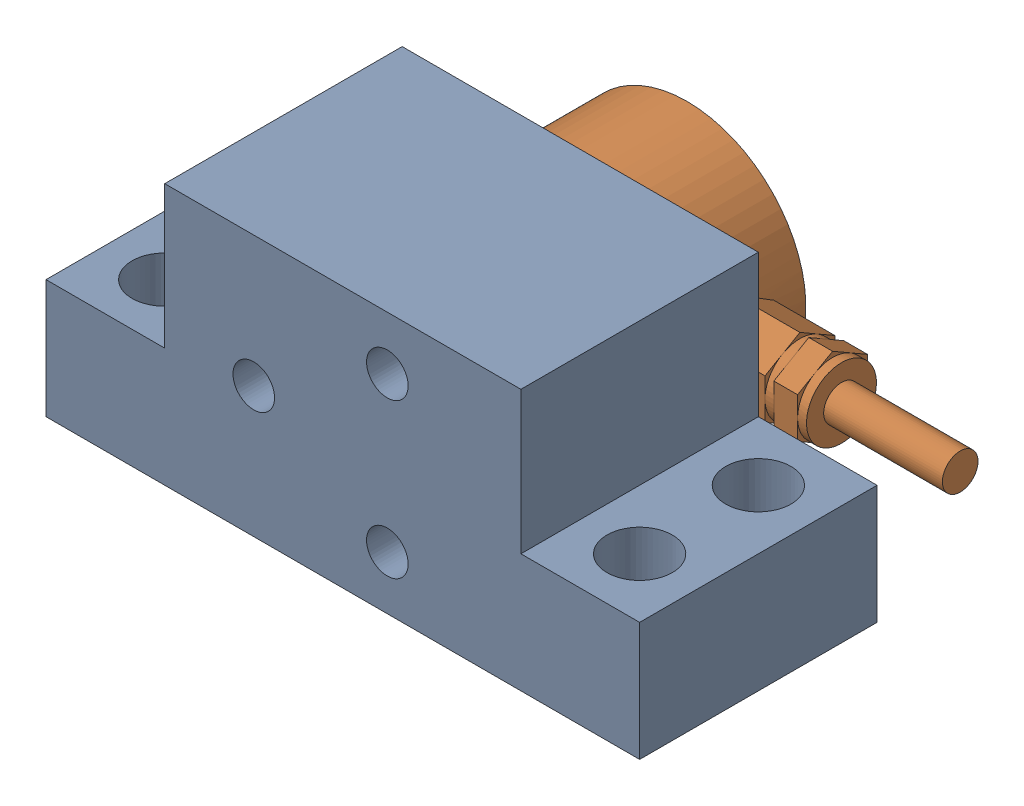
SolidWorks assembly Aynalamaloadcel yatay montaj, configuration Default. Lengths in mm.
Overall size (53.5 22 31).
2 component instances, 2 part files, 0 mates.
Components (placement in the parent):
- AynalamaLoadcell yatay ayak-1: AynalamaLoadcell yatay ayak [Default] at origin size (50 22 20)
- AynalamaMini_Loadcell-1: AynalamaMini_Loadcell [Default] at (0 11 -19) x (-1 0 0) z (0 -1 0) size (38.5 12 20)
